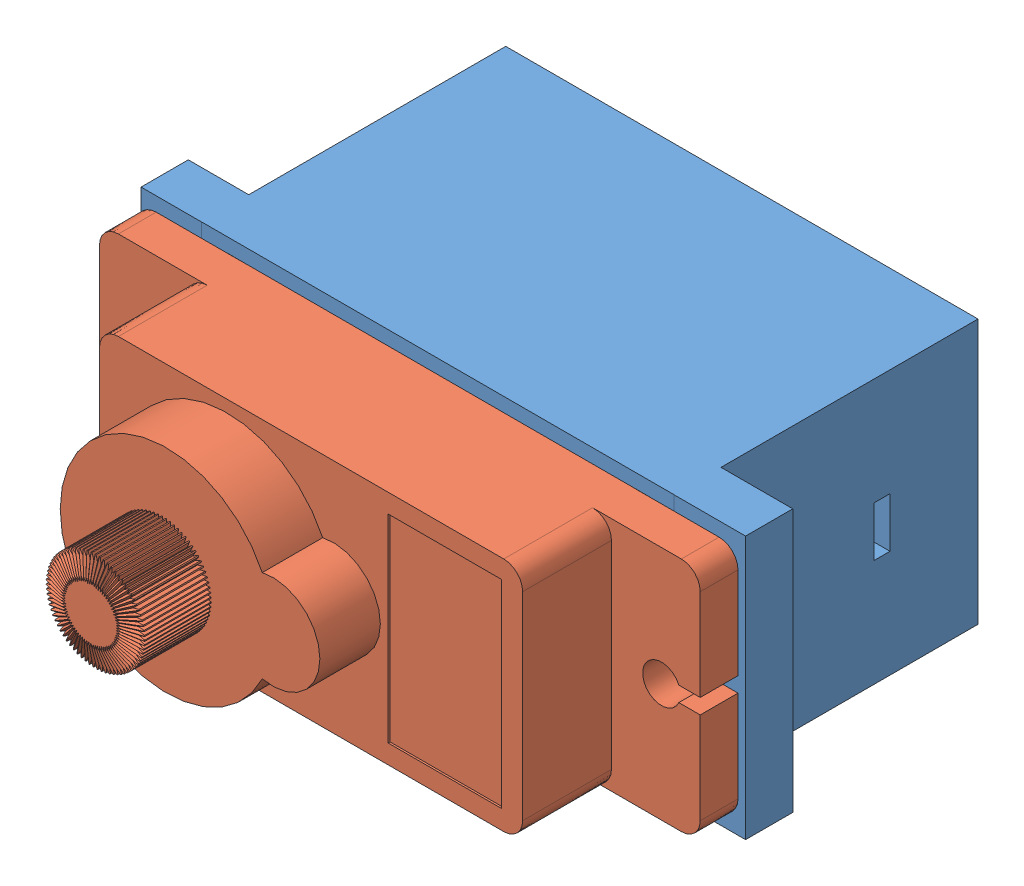
SolidWorks assembly SERVO+HOLDER, configuration Default. Lengths in mm.
Overall size (32.2 14 30).
2 component instances, 2 part files, 3 mates.
Components (placement in the parent):
- holder-1: holder [Default] at (18.9662 16.7221 12.6315) size (32 14 16.1)
- SG90-1: SG90 [Varsayılan] at (30.1662 22.9721 12.6362) x (-1 0 0) z (0 0 1) size (31.8 12.51 30)
Mates (geometry in assembly coordinates):
- Coincident8: coincident: plane of holder-1 through (30.1662 10.4721 28.7315) normal (-1 0 0); plane of SG90-1 through (30.1662 10.4721 28.7362) normal (1 0 0)
- Coincident9: coincident: plane of holder-1 through (7.7662 10.4721 28.7315) normal (0 1 0); plane of SG90-1 through (7.7662 10.4721 28.7362) normal (0 -1 0)
- Coincident10: coincident anti-aligned: plane of holder-1 through (18.9662 16.7221 28.7362) normal (0 0 1); plane of SG90-1 through (30.1662 22.9721 28.7362) normal (0 0 -1)
